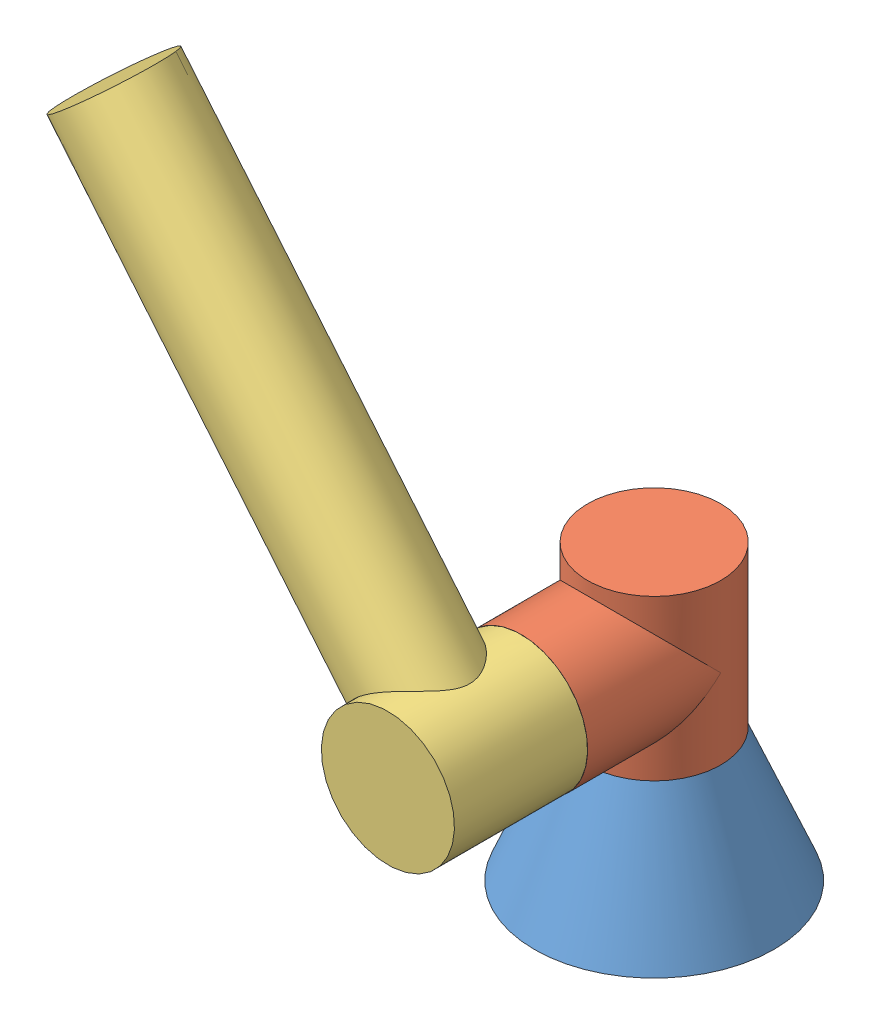
SolidWorks assembly link12, configuration 默认. Lengths in mm.
Overall size (384.32 499.43 410).
3 component instances, 3 part files, 2 mates.
Components (placement in the parent):
- base-1: base [默认] at (11.2599 -69.3759 200) size (180 100 180)
- link1-1: link1 [默认] at (11.2599 90.6241 200) size (100 120 150)
- link2-1: link2 [默认] at (-116.6858 244.3443 350) x (0.639729 -0.768601 0) z (0 0 1) size (450 100 100)
Mates (geometry in assembly coordinates):
- 同心1: concentric aligned: circle of base-1; circle of link1-1
- 重合3: coincident anti-aligned: plane of base-1 through (11.2599 30.6241 200) normal (0 1 0); plane of link1-1 through (11.2599 30.6241 200) normal (0 -1 0)
